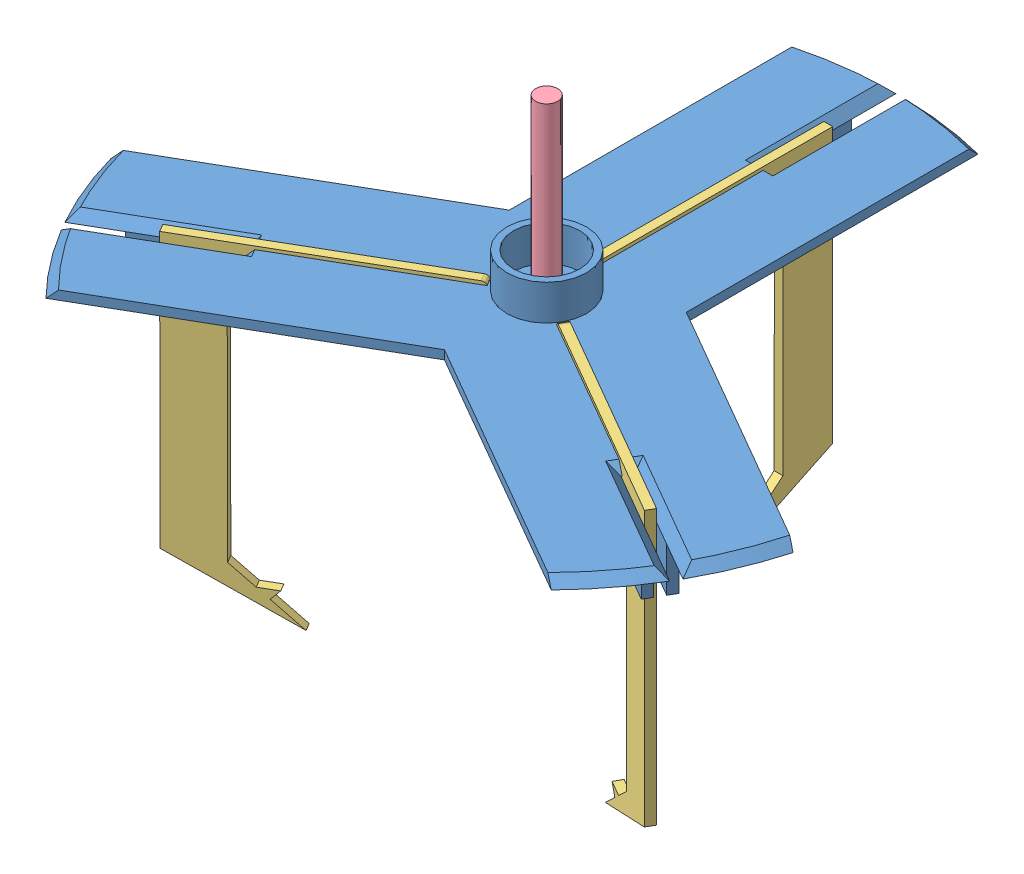
SolidWorks assembly gripping arm, configuration Default. Lengths in mm.
Overall size (154.16 377.93 139.46).
6 component instances, 4 part files, 8 mates.
Components (placement in the parent):
- holder-1: holder [Default] at (57.5052 102.868 110.8238) size (154.16 20 136.04)
- pneumatic to arm-1: pneumatic to arm [Default] at (57.5052 102.9064 110.8238) x (0.999262 0 -0.038423) z (-0.038423 0 -0.999262) size (54.95 10 48.9)
- finger1-1: finger1 [Default] at (49.8561 56.2247 116.5102) x (-0.866025 -0.001259 0.5) z (0.00109 -0.999999 -0.00063) size (54.2 2 73.7)
- rod-1: rod [Default] at (57.5052 93.1767 110.8238) x (0.882577 0 0.470169) z (-0.470169 0 0.882577) size (5 50 5)
- finger1-2: finger1 [Default] at (56.4052 56.2247 101.3563) x (0 -0.001259 -0.999999) z (0 -0.999999 0.001259) size (54.2 2 73.7)
- finger1-3: finger1 [Default] at (66.2543 56.2247 114.605) x (0.866025 -0.001259 0.5) z (-0.00109 -0.999999 -0.00063) size (54.2 2 73.7)
Mates (geometry in assembly coordinates):
- Parallel2: parallel: plane of holder-1 through (60.6052 92.868 60.8238) normal (1 0 0); plane of pneumatic to arm-1
- Concentric6: concentric aligned: circle of holder-1; circle of rod-1
- Concentric7: concentric anti-aligned: circle of holder-1; circle of pneumatic to arm-1
- Parallel7: parallel aligned: plane of holder-1 through (99.2565 92.868 138.5085) normal (-0.5 0 0.866025); plane of pneumatic to arm-1 through (64.2154 92.9064 118.2382) normal (-0.5 0 0.866025)
- Lock2: lock: unknown of pneumatic to arm-1; unknown of rod-1
- Coincident11: coincident anti-aligned: circle of holder-1; circle of finger1-1
- Tangent2: tangent anti-aligned: cylinder of pneumatic to arm-1 through (39.7387 97.9064 129.0881) axis (-0.5 0 -0.866025) radius 2; plane of finger1-1 through (35.8181 99.9064 122.3057) normal (0.00109 -0.999999 -0.00063)
- PathMate2: path: point of ?
